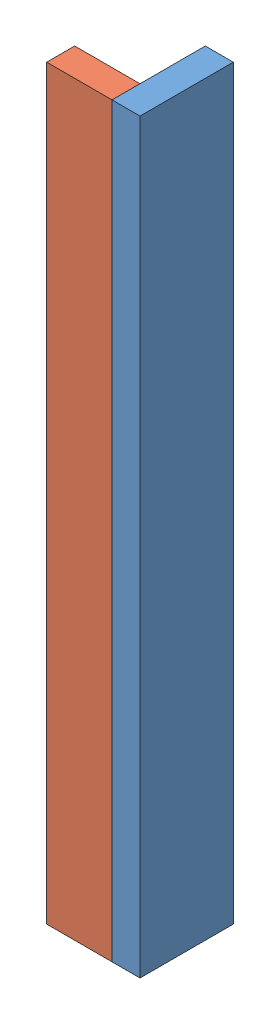
SolidWorks assembly arm_holder_leg, configuration Default. Lengths in mm.
Overall size (10 80 10).
2 component instances, 2 part files, 2 mates.
Components (placement in the parent):
- arm_holder_leg1-1: arm_holder_leg1 [Default] at (25.3885 -63.6916 2.6985) size (3 80 10)
- arm_holder_leg2-1: arm_holder_leg2 [Default] at (0 -63.6916 0) size (10 80 10)
Mates (geometry in assembly coordinates):
- Coincident1: coincident: line of arm_holder_leg1-1 through (23.8885 -63.6916 7.6985) axis (1 0 0); line of arm_holder_leg2-1 through (23.8885 -63.6916 7.6985) axis (-1 0 0)
- Coincident2: coincident aligned: line of arm_holder_leg1-1 through (23.8885 16.3084 7.6985) axis (0 -1 0); line of arm_holder_leg2-1 through (23.8885 16.3084 7.6985) axis (0 -1 0)
